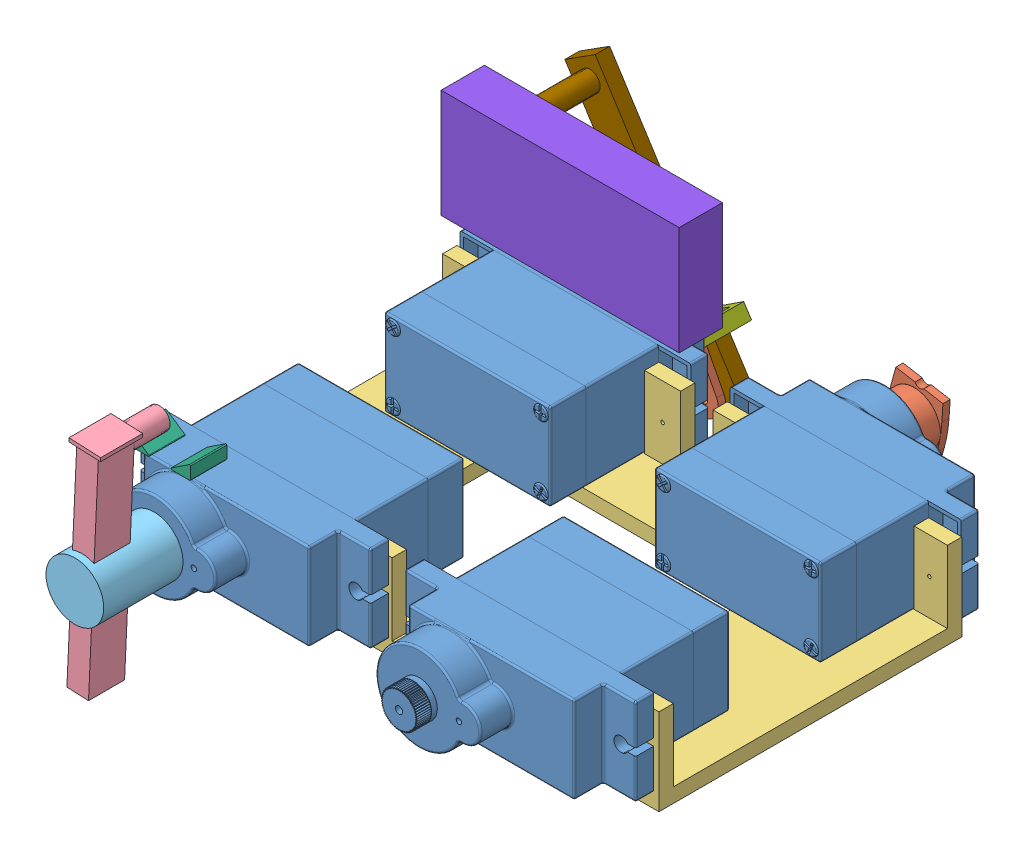
SolidWorks assembly quad_robot, configuration Default. Lengths in mm.
Overall size (72.7 38.42 84.6).
14 component instances, 10 part files, 28 mates.
Components (placement in the parent):
- servo motor assembly-1: servo motor assembly [Default] at (-12.4265 21.3197 12.3212) x (1 0 0) z (0 -1 0) size (32 28.96 12.1)
- servo_motor-1: servo_motor [Default] at (19.4496 21.3197 -35.6788) x (0.9856 -0.169092 0) z (-0.169092 -0.9856 0) size (7.3 5 34)
- Part1^quad_robot-1: Part1^quad_robot [Default] at (6.0638 13.3197 1.3212) size (70 12 42) (virtual)
- servo motor assembly-2: servo motor assembly [Default] at (-12.5264 21.3197 -9.6788) x (1 0 0) z (0 1 0) size (32 28.96 12.1)
- servo motor assembly-7: servo motor assembly [Default] at (24.9496 21.3197 -9.6788) x (1 0 0) z (0 1 0) size (32 28.96 12.1)
- servo motor assembly-8: servo motor assembly [Default] at (24.329 21.3197 12.3212) x (1 0 0) z (0 -1 0) size (32 28.96 12.1)
- servo_motor-3: servo_motor [Default] at (-18.0264 21.3197 -35.6788) x (0.836235 0.548372 0) z (0.548372 -0.836235 0) size (7.3 5 34)
- Part2^quad_robot-1: Part2^quad_robot [Default] at origin (suppressed, hidden, virtual)
- Part5^quad_robot-1: Part5^quad_robot [Default] at (-18.53 8.1735 40.8212) x (0 0 -1) z (0.998948 -0.045855 0) size (10.41 30.5 4.4) (virtual)
- Part6^quad_robot-1: Part6^quad_robot [Default] at (-17.9265 21.3197 38.3212) x (0.045855 0.998948 0) z (0 0 -1) size (8 8 11) (virtual)
- Part7^quad_robot-1: Part7^quad_robot [Default] at (-19.3972 30.5937 27.3212) size (8.54 13.87 5) (virtual)
- Part2^quad_robot-2: Part2^quad_robot [Default] at (-12.8679 13.4533 -35.4288) x (-0.836235 -0.548372 0) z (0 0 -1) size (10 2 6.6) (virtual)
- Part3^quad_robot-1: Part3^quad_robot [Default] at (-13.6379 32.3197 -21.1788) x (-1 0 0) z (0 -1 0) size (33 6 33.99)
- Part4^quad_robot-1: Part4^quad_robot [Default] at (-28.3757 39.985 -37.1788) x (0.842583 0.538566 0) z (0.538566 -0.842583 0) size (5 17 40) (virtual)
Mates (geometry in assembly coordinates):
- Coincident1: coincident anti-aligned: plane of servo motor assembly-1 through (-12.4265 15.3197 22.3212) normal (0 -1 0); plane of Part1^quad_robot-1 through (6.0638 15.3197 1.3212) normal (0 1 0)
- Coincident2: coincident aligned: plane of servo motor assembly-1 through (-23.9362 21.3197 16.3212) normal (-1 0 0); plane of Part1^quad_robot-1 through (-23.9362 15.3197 -13.6788) normal (-1 0 0)
- Coincident3: coincident anti-aligned: plane of servo motor assembly-1 through (-12.4265 21.3197 22.3212) normal (0 0 -1); plane of Part1^quad_robot-1 through (-28.9362 15.3197 22.3212) normal (0 0 1)
- Coincident4: coincident anti-aligned: plane of Part1^quad_robot-1 through (6.0638 15.3197 1.3212) normal (0 1 0); plane of servo motor assembly-2 through (-12.5264 15.3197 -19.6788) normal (0 -1 0)
- Coincident5: coincident anti-aligned: plane of Part1^quad_robot-1 through (-28.9362 15.3197 -19.6788) normal (0 0 -1); plane of servo motor assembly-2 through (-12.5264 21.3197 -19.6788) normal (0 0 1)
- Coincident10: coincident anti-aligned: plane of Part1^quad_robot-1 through (-28.9362 15.3197 -19.6788) normal (0 0 -1); plane of servo motor assembly-7 through (24.9496 21.3197 -19.6788) normal (0 0 1)
- Coincident15: coincident anti-aligned: circle of servo motor assembly-2; plane of servo_motor-3 through (-18.0264 21.3197 -30.6788) normal (0 0 1)
- Coincident20: coincident aligned: plane of servo motor assembly-7 through (24.9496 15.3197 -19.6788) normal (0 -1 0); plane of servo motor assembly-8 through (24.329 15.3197 22.3212) normal (0 -1 0)
- Concentric5: concentric aligned: cylinder of servo_motor-1 through (19.4496 21.3197 -30.6788) axis (0 0 -1) radius 0.75; cylinder of servo motor assembly-7 through (19.4496 21.3197 20.0213) axis (0 0 -1) radius 0.5
- Coincident24: coincident anti-aligned: plane of servo_motor-1 through (19.4496 21.3197 -30.6788) normal (0 0 1); plane of servo motor assembly-7 through (22.335 22.8153 -30.6788) normal (0 0 -1)
- Coincident25: coincident anti-aligned: plane of Part1^quad_robot-1 through (-28.9362 15.3197 22.3212) normal (0 0 1); plane of servo motor assembly-8 through (24.329 21.3197 22.3212) normal (0 0 -1)
- Coincident26: coincident anti-aligned: plane of Part1^quad_robot-1 through (6.0638 15.3197 1.3212) normal (0 1 0); plane of servo motor assembly-8 through (24.329 15.3197 22.3212) normal (0 -1 0)
- Distance1: distance = 0.5 mm aligned: plane of Part1^quad_robot-1 through (41.0638 15.3197 -13.6788) normal (1 0 0); plane of servo motor assembly-8 through (40.5638 21.3197 16.3212) normal (1 0 0)
- Coincident28: coincident anti-aligned: cylinder of servo motor assembly-1 through (-17.9265 21.3197 24.2002) axis (0 0 1) radius 2.5; circle of Part6^quad_robot-1
- Coincident29: coincident anti-aligned: plane of servo motor assembly-1 through (-15.0411 19.8241 33.3212) normal (0 0 1); plane of Part6^quad_robot-1 through (-17.9265 21.3197 33.3212) normal (0 0 -1)
- Coincident30: coincident anti-aligned: plane of Part5^quad_robot-1 through (-15.6559 38.0732 38.3212) normal (0.998948 -0.045855 0); plane of Part6^quad_robot-1 through (-16.4281 21.2509 43.3212) normal (-0.998948 0.045855 0)
- Coincident31: coincident anti-aligned: plane of Part5^quad_robot-1 through (-15.6559 38.0732 43.3212) normal (0 0 1); plane of Part6^quad_robot-1 through (-17.9265 21.3197 43.3212) normal (0 0 -1)
- LimitDistance1: limit distance = 9.16 mm aligned: plane of Part5^quad_robot-1 through (-18.53 8.1735 40.8212) normal (-0.045855 -0.998948 0); cylinder of Part6^quad_robot-1 through (-17.9265 21.3197 33.3212) axis (0 0 1) radius 4
- Concentric7: concentric aligned: cylinder of servo motor assembly-2 through (-18.0264 21.3197 20.0213) axis (0 0 -1) radius 0.5; cylinder of servo_motor-3 through (-18.0264 21.3197 -30.6788) axis (0 0 -1) radius 3.6484
- Lock1: lock: unknown of servo motor assembly-1; unknown of Part1^quad_robot-1
- Lock2: lock: unknown of Part1^quad_robot-1; unknown of servo motor assembly-2
- Coincident34: coincident anti-aligned: plane of servo_motor-3 through (-26.1149 33.6541 -34.6788) normal (0 0 1); plane of Part2^quad_robot-2 through (-12.0832 16.3596 -34.6788) normal (0 0 -1)
- Coincident36: coincident anti-aligned: plane of servo_motor-3; plane of Part2^quad_robot-2
- Lock3: lock: unknown of servo_motor-3; unknown of Part2^quad_robot-2
- Coincident38: coincident aligned: plane of servo motor assembly-2 through (-12.5264 21.3197 -26.1788) normal (0 0 -1); plane of Part3^quad_robot-1 through (-13.6379 32.3197 -26.1788) normal (0 0 -1)
- Coincident39: coincident anti-aligned: plane of servo motor assembly-2 through (-24.0264 27.3197 -19.6788) normal (0 1 0); plane of Part3^quad_robot-1 through (-13.6379 27.3197 -26.1788) normal (0 -1 0)
- PathMate3: path: point of Part4^quad_robot-1; curve of Part3^quad_robot-1; curve of Part3^quad_robot-1
- Parallel5: parallel: line of Part3^quad_robot-1 through (-15.1379 47.5721 -21.1788) axis (0 -1 0); plane of Part4^quad_robot-1 through (-8.9395 4.9352 -38.1788) normal (0 0 -1)
